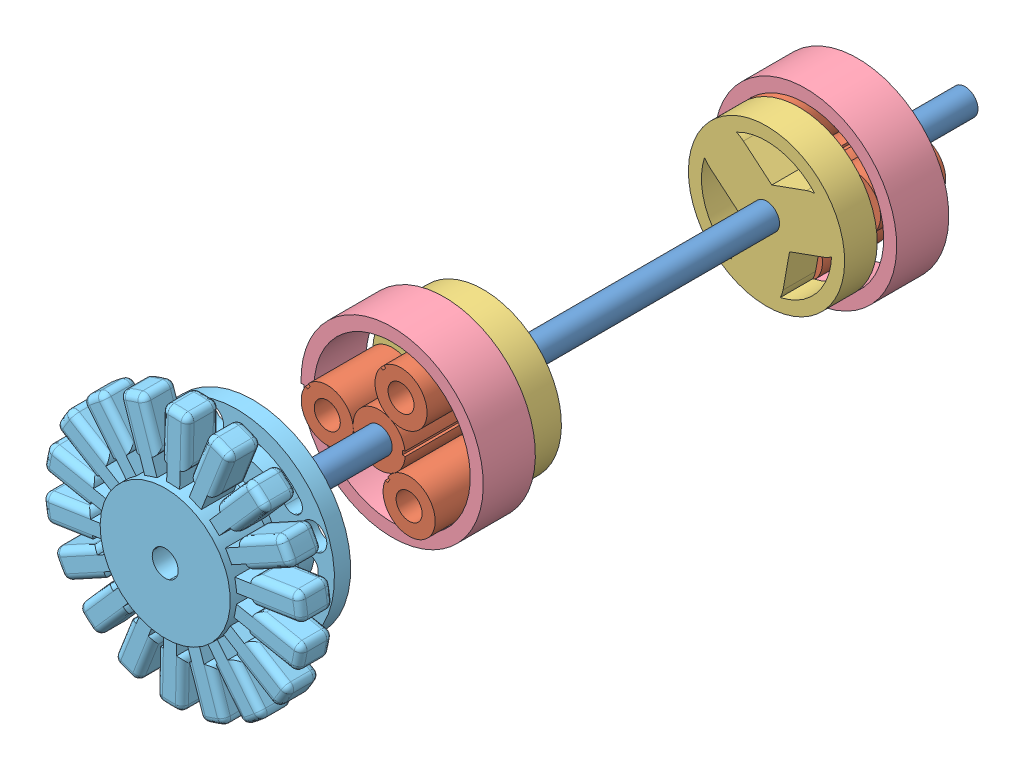
SolidWorks assembly Assem2, configuration Default. Lengths in mm.
Overall size (50.46 50.63 122.86).
15 component instances, 6 part files, 45 mates.
Components (placement in the parent):
- shaft-2: shaft [Default] at (-4.8863 -2.0167 -2.6517) x (0.988326 -0.152353 0) z (0 0 1) size (4 4 120)
- sungear-1: sungear [Default] at (-4.8863 -2.0167 77.3483) x (-0.156817 -0.987628 0) z (0 0 1) size (8 8 10)
- spider-1: spider [Default] at (-4.8863 -2.0167 71.3483) x (-0.089826 0.995957 0) z (0 0 1) size (24 24 10)
- sungear-2: sungear [Default] at (-0.2801 -8.5576 77.3483) x (0.642236 0.766507 0) z (0 0 1) size (8 8 10)
- ring gear-1: ring gear [Default] at (-4.8863 -2.0167 77.3483) x (-0.084616 0.996414 0) z (0 0 1) size (28 27.98 8)
- ring gear-2: ring gear [Default] at (-4.8863 -2.0167 13.8375) x (-0.195813 0.980641 0) z (0 0 1) size (28 27.98 8)
- motor rotor-1: motor rotor [Default] at (-4.8863 -2.0167 114.2125) x (-0.32105 0.947062 0) z (0.947062 0.32105 0) size (40 13.5 39.72)
- sungear-5: sungear [Default] at (-12.8539 -2.7353 77.3483) x (0.753017 0.658001 0) z (0 0 1) size (8 8 10)
- sungear-6: sungear [Default] at (-1.5248 5.2428 77.3483) x (0.816451 0.577415 0) z (0 0 1) size (8 8 10)
- sungear-7: sungear [Default] at (-4.8863 -2.0167 11.8375) x (0.931612 -0.363454 0) z (0 0 1) size (8 8 10)
- sungear-8: sungear [Default] at (-11.0054 3.1366 11.8375) x (-0.732015 0.681289 0) z (0 0 1) size (8 8 10)
- sungear-9: sungear [Default] at (-6.2896 -9.8926 11.8375) x (0.991765 0.128069 0) z (0 0 1) size (8 8 10)
- sungear-10: sungear [Default] at (2.6362 0.706 11.8375) x (-0.858526 0.51277 0) z (0 0 1) size (8 8 10)
- spider-3: spider [Default] at (-4.8863 -2.0167 27.8375) x (-0.340332 0.940305 0) z (0 0 -1) size (24 24 10)
- switch case-1: switch case [Default] at (-4.8863 -2.0167 49.4509) x (0 0 -1) z (1 0 0) size (91.87 38.94 40) (hidden)
Mates (geometry in assembly coordinates):
- Concentric1: concentric aligned: cylinder of shaft-2 through (-4.8863 -2.0167 117.3483) axis (0 0 -1) radius 2; cylinder of sungear-1 through (-4.8863 -2.0167 87.3483) axis (0 0 -1) radius 2
- Distance1: distance = 80 mm aligned: plane of shaft-2 through (-4.8863 -2.0167 -2.6517) normal (0 0 -1); plane of sungear-1 through (-4.8863 -2.0167 77.3483) normal (0 0 -1)
- Concentric2: concentric anti-aligned: cylinder of sungear-1 through (-4.8863 -2.0167 87.3483) axis (0 0 -1) radius 2; cylinder of spider-1 through (-4.8863 -2.0167 71.3483) axis (0 0 1) radius 2
- Distance2: distance = 1 mm anti-aligned: plane of spider-1 through (-12.8539 -2.7353 76.3483) normal (0 0 1); plane of sungear-1 through (-4.8863 -2.0167 77.3483) normal (0 0 -1)
- Concentric3: concentric aligned: cylinder of spider-1 through (-0.2801 -8.5576 81.3483) axis (0 0 -1) radius 2; cylinder of sungear-2 through (-0.2801 -8.5576 87.3483) axis (0 0 -1) radius 2
- Coincident3: coincident aligned: plane of sungear-1 through (-4.8863 -2.0167 77.3483) normal (0 0 -1); plane of sungear-2 through (-0.2801 -8.5576 77.3483) normal (0 0 -1)
- GearMate1: gear = 8 : 8 mm: cylinder of sungear-1 through (-4.8863 -2.0167 87.3483) axis (0 0 -1) radius 4; cylinder of sungear-2 through (-0.2801 -8.5576 87.3483) axis (0 0 -1) radius 4
- Concentric4: concentric aligned: cylinder of shaft-2 through (-4.8863 -2.0167 117.3483) axis (0 0 -1) radius 2; cylinder of ring gear-1 through (-4.8863 -2.0167 85.3483) axis (0 0 -1) radius 14
- Coincident4: coincident aligned: plane of sungear-2 through (-0.2801 -8.5576 77.3483) normal (0 0 -1); plane of ring gear-1 through (-4.8863 -2.0167 77.3483) normal (0 0 -1)
- GearMate2: gear = 24 : 8 mm: cylinder of sungear-2 through (-0.2801 -8.5576 87.3483) axis (0 0 -1) radius 4; cylinder of ring gear-1 through (-4.8863 -2.0167 85.3483) axis (0 0 -1) radius 12
- Concentric7: concentric aligned: cylinder of ring gear-1 through (-4.8863 -2.0167 85.3483) axis (0 0 -1) radius 14; cylinder of ring gear-2 through (-4.8863 -2.0167 21.8375) axis (0 0 -1) radius 14
- Concentric9: concentric aligned: cylinder of spider-1 through (-12.8539 -2.7353 81.3483) axis (0 0 -1) radius 2; cylinder of sungear-5 through (-12.8539 -2.7353 87.3483) axis (0 0 -1) radius 2
- Coincident7: coincident aligned: plane of sungear-2 through (-0.2801 -8.5576 87.3483) normal (0 0 1); plane of sungear-5 through (-12.8539 -2.7353 87.3483) normal (0 0 1)
- Concentric10: concentric aligned: cylinder of spider-1 through (-1.5248 5.2428 81.3483) axis (0 0 -1) radius 2; cylinder of sungear-6 through (-1.5248 5.2428 87.3483) axis (0 0 -1) radius 2
- Coincident8: coincident aligned: plane of sungear-5 through (-12.8539 -2.7353 87.3483) normal (0 0 1); plane of sungear-6 through (-1.5248 5.2428 87.3483) normal (0 0 1)
- GearMate3: gear = 8 : 8 mm: cylinder of sungear-5 through (-12.8539 -2.7353 87.3483) axis (0 0 -1) radius 4; cylinder of sungear-1 through (-4.8863 -2.0167 87.3483) axis (0 0 -1) radius 4
- GearMate4: gear = 8 : 8 mm: cylinder of sungear-6 through (-1.5248 5.2428 87.3483) axis (0 0 -1) radius 4; cylinder of sungear-1 through (-4.8863 -2.0167 87.3483) axis (0 0 -1) radius 4
- Concentric11: concentric aligned: cylinder of shaft-2 through (-4.8863 -2.0167 117.3483) axis (0 0 -1) radius 2; cylinder of motor rotor-1 through (-4.8863 -2.0167 119.2125) axis (0 0 -1) radius 2
- Concentric13: concentric anti-aligned: cylinder of shaft-2 through (-4.8863 -2.0167 117.3483) axis (0 0 -1) radius 2; cylinder of spider-2 through (-4.8863 -2.0167 18.7839) axis (0 0 1) radius 2
- Concentric15: concentric aligned: cylinder of shaft-2 through (-4.8863 -2.0167 117.3483) axis (0 0 -1) radius 2; cylinder of sungear-7 through (-4.8863 -2.0167 21.8375) axis (0 0 -1) radius 2
- Concentric16: concentric aligned: cylinder of shaft-2 through (-4.8863 -2.0167 117.3483) axis (0 0 -1) radius 2; cylinder of Part6-1 through (0 0 90.3483) axis (0 0 -1) radius 7
- Distance3: distance = 1 mm anti-aligned: plane of spider-1 through (-12.8539 -2.7353 71.3483) normal (0 0 -1); plane of Part6-1 through (15.2466 -14.3036 73.3483) normal (0 0 1)
- Concentric17: concentric aligned: cylinder of shaft-2 through (-4.8863 -2.0167 117.3483) axis (0 0 -1) radius 2; circle of Part6-2
- Coincident11: coincident aligned: plane of Part6-1 through (15.2466 -14.3036 43.3483) normal (0.083437 -0.996513 0); plane of Part6-2 through (15.2466 -14.3036 -16.4793) normal (0.083437 -0.996513 0)
- Distance4: distance = 1 mm anti-aligned: plane of sungear-7 through (-4.8863 -2.0167 11.8375) normal (0 0 -1); plane of spider-2 through (-0.174 4.4482 23.7839) normal (0 0 1)
- Distance5: distance = 59.8277 mm aligned: plane of Part6-1 through (15.2466 -14.3036 43.3483) normal (0 0 -1); plane of Part6-2 through (15.2466 -14.3036 -16.4793) normal (0 0 -1)
- Concentric18: concentric aligned: line of spider-2 through (-1.6436 -9.33 28.7839) axis (0 0 -1); cylinder of sungear-8 through (-1.6436 -9.33 34.7839) axis (0 0 -1) radius 2
- Concentric19: concentric aligned: cylinder of spider-2 through (-12.8411 -1.1682 28.7839) axis (0 0 -1) radius 2; cylinder of sungear-10 through (2.6362 0.706 21.8375) axis (0 0 -1) radius 2
- Concentric20: concentric aligned: cylinder of spider-2 through (-0.174 4.4482 28.7839) axis (0 0 -1) radius 2; cylinder of sungear-9 through (-6.2896 -9.8926 21.8375) axis (0 0 -1) radius 2
- Concentric21: concentric anti-aligned: cylinder of spider-1 through (-4.8863 -2.0167 37.4072) axis (0 0 1) radius 12; cylinder of mags_1-1 through (-4.8863 -2.0167 76.3483) axis (0 0 -1) radius 15
- Coincident16: coincident aligned: plane of spider-1 through (-12.8539 -2.7353 76.3483) normal (0 0 1); plane of mags_1-1 through (-4.8863 -2.0167 76.3483) normal (0 0 1)
- Coincident17: coincident aligned: plane of ring gear-1 through (-4.8863 -2.0167 85.3483) normal (0 0 1); plane of mags_2-1 through (-4.8863 -2.0167 85.3483) normal (0 0 1)
- Concentric22: concentric aligned: cylinder of ring gear-1 through (-4.8863 -2.0167 85.3483) axis (0 0 -1) radius 14; cylinder of mags_2-1 through (-4.8863 -2.0167 85.3483) axis (0 0 -1) radius 27.5
- Coincident18: coincident aligned: plane of mags_1-1 through (-7.2281 12.7994 76.3483) normal (0.987737 0.156124 0); plane of mags_2-1 through (-0.3569 14.887 85.3483) normal (0.965926 -0.258819 0)
- Concentric24: concentric aligned: cylinder of shaft-2 through (-4.8863 -2.0167 117.3483) axis (0 0 -1) radius 2; cylinder of spider-3 through (-4.8863 -2.0167 27.8375) axis (0 0 -1) radius 2
- Concentric25: concentric anti-aligned: cylinder of sungear-8 through (-11.0054 3.1366 21.8375) axis (0 0 -1) radius 2; cylinder of spider-3 through (-11.0054 3.1366 17.8375) axis (0 0 1) radius 2
- Concentric27: concentric anti-aligned: cylinder of sungear-10 through (2.6362 0.706 21.8375) axis (0 0 -1) radius 2; cylinder of spider-3 through (2.6362 0.706 17.8375) axis (0 0 1) radius 2
- Concentric28: concentric anti-aligned: cylinder of sungear-9 through (-6.2896 -9.8926 21.8375) axis (0 0 -1) radius 2; cylinder of spider-3 through (-6.2896 -9.8926 17.8375) axis (0 0 1) radius 2
- Coincident21: coincident aligned: plane of ring gear-2 through (-4.8863 -2.0167 21.8375) normal (0 0 1); plane of sungear-9 through (-6.2896 -9.8926 21.8375) normal (0 0 1)
- Coincident23: coincident aligned: plane of ring gear-2 through (-4.8863 -2.0167 21.8375) normal (0 0 1); plane of sungear-10 through (2.6362 0.706 21.8375) normal (0 0 1)
- Distance6: distance = 1 mm anti-aligned: plane of ring gear-2 through (-4.8863 -2.0167 21.8375) normal (0 0 1); plane of spider-3 through (2.6362 0.706 22.8375) normal (0 0 -1)
- Coincident25: coincident aligned: plane of ring gear-2 through (-4.8863 -2.0167 21.8375) normal (0 0 1); plane of sungear-8 through (-11.0054 3.1366 21.8375) normal (0 0 1)
- Coincident26: coincident aligned: plane of sungear-7 through (-4.8863 -2.0167 11.8375) normal (0 0 -1); plane of sungear-9 through (-6.2896 -9.8926 11.8375) normal (0 0 -1)
- Concentric29: concentric anti-aligned: line of shaft-2 through (-4.8863 -2.0167 117.3483) axis (0 0 -1); cylinder of switch case-1 through (-4.8863 -2.0167 78.8349) axis (0 0 1) radius 20
- Parallel1: parallel aligned: plane of motor rotor-1 through (-7.7067 -21.8294 -185.5) normal (0 -1 0); plane of switch case-1 through (18.3923 -20.9536 95.3878) normal (0 -1 0)
